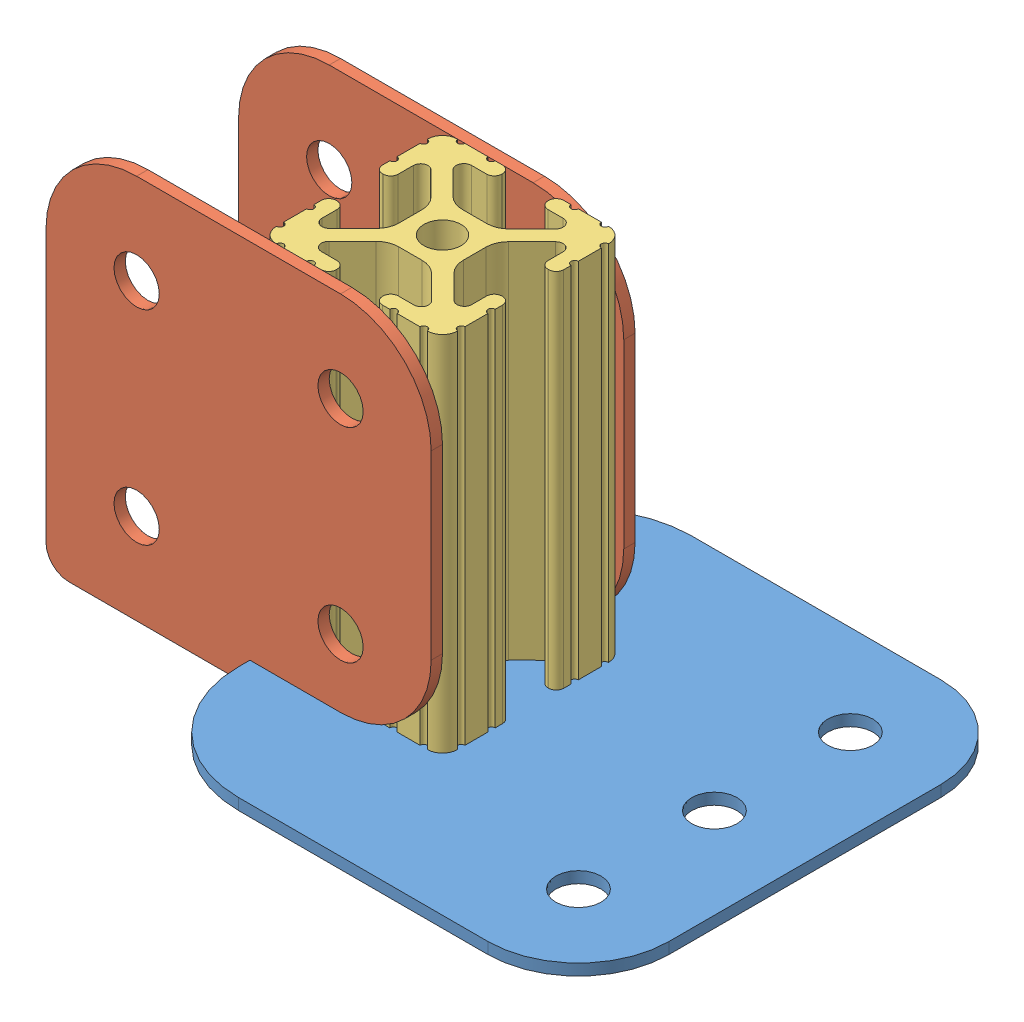
SolidWorks assembly 8020 Leg Piece, configuration Default. Lengths in mm.
Overall size (92.07 53.97 63.5).
4 component instances, 3 part files, 9 mates.
Components (placement in the parent):
- 8020 Base Section-1: 8020 Base Section [Default] at (42.6282 29.8358 88.9631) size (63.5 1.59 63.5)
- 8020 Side Section-1: 8020 Side Section [Default] at (4.5282 31.4233 42.9256) size (53.98 53.97 1.59)
- 8020 Side Section-2: 8020 Side Section [Default] at (4.5282 31.4233 69.9131) size (53.98 53.97 1.59)
- 8020 - 2ft-1: 8020 - 2ft [47065T209] at (-8.1718 56.8233 57.2131) x (1 0 0) z (0 -1 0) size (25.4 25.4 50.8)
Mates (geometry in assembly coordinates):
- Concentric1: concentric anti-aligned: cylinder of 8020 Base Section-1 through (-8.1718 31.4233 57.2131) axis (0 -1 0) radius 3.175; cylinder of 8020 - 2ft-1 through (-8.1718 31.4233 57.2131) axis (0 1 0) radius 2.6035
- Coincident1: coincident anti-aligned: plane of 8020 Base Section-1 through (42.6282 31.4233 88.9631) normal (0 1 0); plane of 8020 - 2ft-1 through (-14.5882 31.4233 47.8033) normal (0 -1 0)
- Coincident2: coincident aligned: plane of 8020 Base Section-1 through (-20.8718 31.4233 88.9631) normal (-1 0 0); plane of 8020 - 2ft-1 through (-20.8718 31.4233 66.7635) normal (-1 0 0)
- Coincident3: coincident anti-aligned: plane of 8020 Base Section-1 through (-20.8718 31.4233 88.9631) normal (-1 0 0); plane of 8020 Side Section-2 through (-20.8718 31.4233 71.5006) normal (1 0 0)
- Coincident4: coincident anti-aligned: plane of 8020 Base Section-1 through (-20.8718 31.4233 88.9631) normal (-1 0 0); plane of 8020 Side Section-1 through (-20.8718 31.4233 44.5131) normal (1 0 0)
- Coincident5: coincident anti-aligned: plane of 8020 Base Section-1 through (42.6282 31.4233 88.9631) normal (0 1 0); plane of 8020 Side Section-1 through (4.5282 31.4233 44.5131) normal (0 -1 0)
- Coincident6: coincident anti-aligned: plane of 8020 Base Section-1 through (42.6282 31.4233 88.9631) normal (0 1 0); plane of 8020 Side Section-2 through (4.5282 31.4233 71.5006) normal (0 -1 0)
- Coincident7: coincident anti-aligned: plane of 8020 Side Section-2 through (4.5282 31.4233 69.9131) normal (0 0 -1); plane of 8020 - 2ft-1 through (-14.5049 31.4233 69.9131) normal (0 0 1)
- Coincident8: coincident anti-aligned: plane of 8020 Side Section-1 through (4.5282 31.4233 44.5131) normal (0 0 1); plane of 8020 - 2ft-1 through (-1.8386 31.4233 44.5131) normal (0 0 -1)
